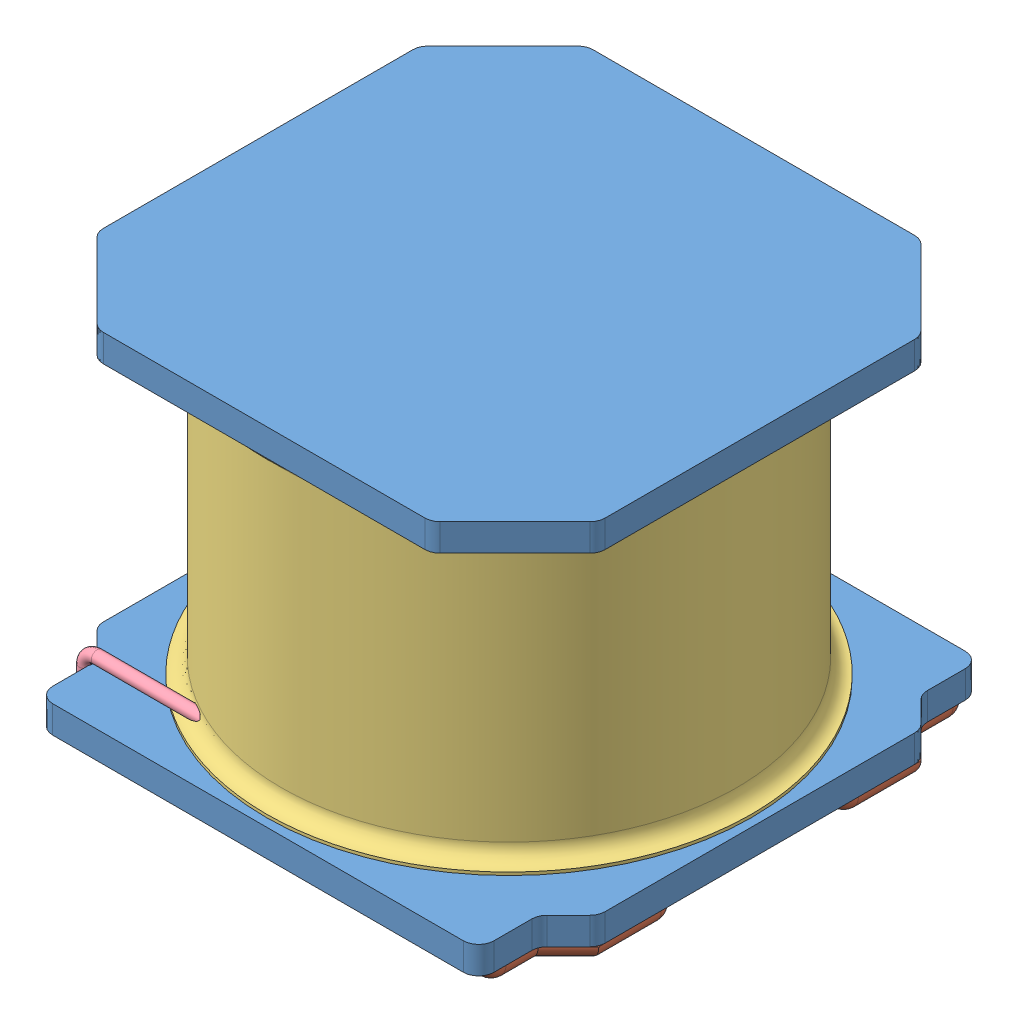
SolidWorks assembly coil, configuration Default. Lengths in mm.
Overall size (5.97 4.56 5.97).
5 component instances, 4 part files, 0 mates.
Components (placement in the parent):
- coil.stp-1: coil.stp [Default] at origin size (5.97 4.56 5.97)
  - Body.stp-1: Body.stp [Default] at origin size (5.97 4.38 5.97)
  - Pins.stp-1: Pins.stp [Default] at (0 0 0.5665) x (-1 0 0) z (0 0 -1) size (5.97 0.18 5.68)
  - Sealant.stp-1: Sealant.stp [Default] at (0 0.3515 0) size (5.77 3.73 5.77)
  - wire.stp-1: wire.stp [Default] at (-0.3372 0.4779 0.6934) x (1 0 0) z (0 0 -1) size (2.81 0.65 4.83)
